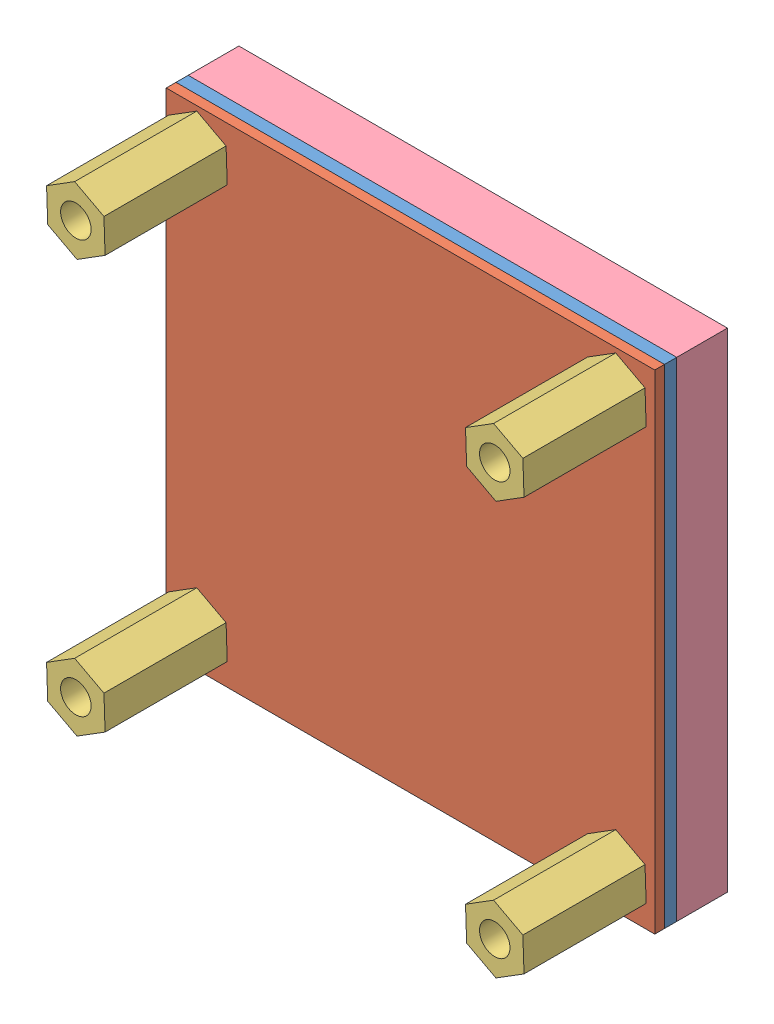
SolidWorks assembly Assem1, configuration Default. Lengths in mm.
Overall size (40 40 16).
7 component instances, 4 part files, 14 mates.
Components (placement in the parent):
- 1559_B-1: 1559_B [Default] at (8.4797 17.3877 36.4763) size (40 40 1)
- pcb-1: pcb [Default] at (8.4797 17.3877 37.4763) size (40 40 0.8)
- standoff-1: standoff [Default] at (-8.9203 34.2877 48.2763) x (-1 0 0) z (0 0 -1) size (4.79 5.42 10)
- standoff-2: standoff [Default] at (-8.9203 0.4877 48.2763) x (-1 0 0) z (0 0 -1) size (4.79 5.42 10)
- standoff-3: standoff [Default] at (25.3797 34.2877 48.2763) x (-1 0 0) z (0 0 -1) size (4.79 5.42 10)
- standoff-4: standoff [Default] at (25.3797 0.4877 48.2763) x (-1 0 0) z (0 0 -1) size (4.79 5.42 10)
- asasdfsdaf-1: asasdfsdaf [Default] at (8.4797 17.3877 36.4763) x (1 0 0) z (0 0 -1) size (40 40 4.2)
Mates (geometry in assembly coordinates):
- Coincident1: coincident anti-aligned: plane of 1559_B-1 through (8.4797 17.3877 37.4763) normal (0 0 1); plane of pcb-1 through (8.4797 17.3877 37.4763) normal (0 0 -1)
- Coincident2: coincident aligned: plane of 1559_B-1 through (-11.5203 -2.6123 37.4763) normal (0 -1 0); plane of pcb-1 through (-11.5203 -2.6123 38.2763) normal (0 -1 0)
- Coincident3: coincident aligned: plane of 1559_B-1 through (28.4797 37.3877 37.4763) normal (1 0 0); plane of pcb-1 through (28.4797 37.3877 38.2763) normal (1 0 0)
- Coincident4: coincident anti-aligned: plane of pcb-1 through (8.4797 17.3877 38.2763) normal (0 0 1); plane of standoff-1 through (-8.9203 34.2877 38.2763) normal (0 0 -1)
- Concentric1: concentric aligned: circle of 1559_B-1; cylinder of standoff-1 through (-8.9203 34.2877 43.2763) axis (0 0 1) radius 1.25
- Coincident5: coincident anti-aligned: plane of pcb-1 through (8.4797 17.3877 38.2763) normal (0 0 1); plane of standoff-2 through (-8.9203 0.4877 38.2763) normal (0 0 -1)
- Concentric2: concentric aligned: circle of 1559_B-1; cylinder of standoff-2 through (-8.9203 0.4877 43.2763) axis (0 0 1) radius 1.25
- Coincident6: coincident anti-aligned: plane of pcb-1 through (8.4797 17.3877 38.2763) normal (0 0 1); plane of standoff-3 through (25.3797 34.2877 38.2763) normal (0 0 -1)
- Concentric3: concentric aligned: circle of 1559_B-1; cylinder of standoff-3 through (25.3797 34.2877 43.2763) axis (0 0 1) radius 1.25
- Coincident7: coincident anti-aligned: plane of pcb-1 through (8.4797 17.3877 38.2763) normal (0 0 1); plane of standoff-4 through (25.3797 0.4877 38.2763) normal (0 0 -1)
- Concentric4: concentric aligned: circle of 1559_B-1; cylinder of standoff-4 through (25.3797 0.4877 43.2763) axis (0 0 1) radius 1.25
- Coincident8: coincident: plane of 1559_B-1 through (8.4797 17.3877 36.4763) normal (0 0 -1); plane of asasdfsdaf-1 through (8.4797 17.3877 36.4763) normal (0 0 1)
- Coincident9: coincident: plane of 1559_B-1 through (-11.5203 -2.6123 37.4763) normal (0 -1 0); plane of asasdfsdaf-1 through (-11.5203 -2.6123 32.3263) normal (0 -1 0)
- Coincident10: coincident aligned: plane of 1559_B-1 through (28.4797 37.3877 37.4763) normal (1 0 0); plane of asasdfsdaf-1 through (28.4797 -2.6123 32.3263) normal (1 0 0)
